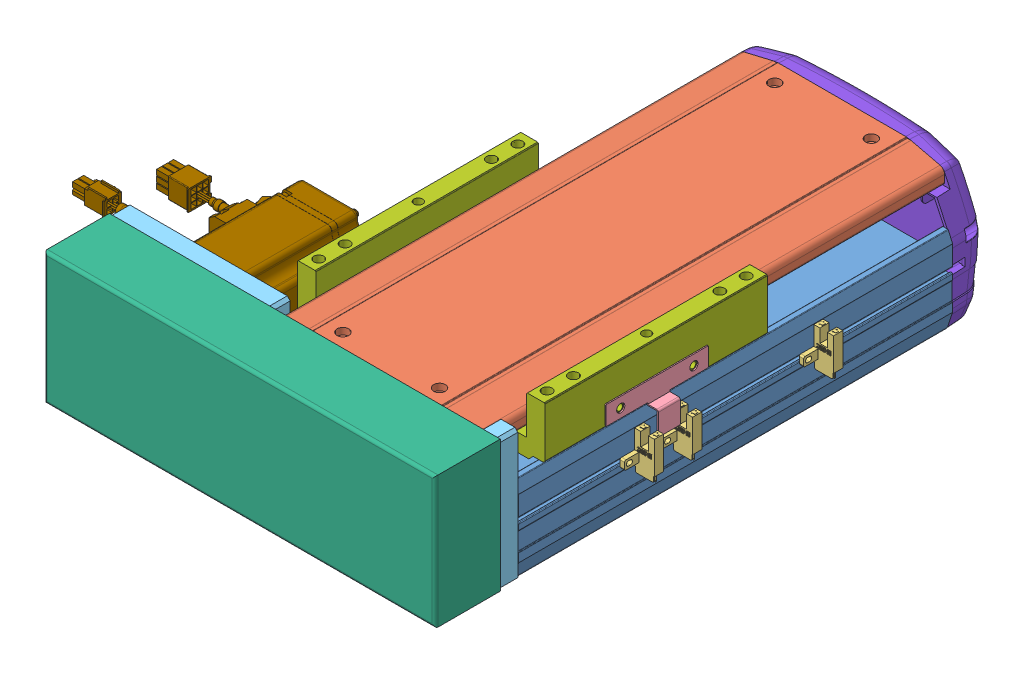
SolidWorks assembly S17-BR-400W, configuration 默认. Lengths in mm.
Overall size (347.7 97.04 383.22).
11 component instances, 9 part files, 40 mates.
Components (placement in the parent):
- S17-BM底座^S17-BR-400W-1: S17-BM底座^S17-BR-400W [默认] at origin size (170 59.5 313.5) (virtual)
- S17-BM上盖^S17-BR-400W-2: S17-BM上盖^S17-BR-400W [默认] at (0 90.5 7.5) size (140 15.5 318) (virtual)
- EE-SX672 传感器^S17-BR-400W-1: EE-SX672 传感器^S17-BR-400W [默认] at (91.7485 41.1 234.2) x (1 0 0) z (0 0 -1) size (13.5 27.4 26.1) (virtual)
- EE-SX672 传感器^S17-BR-400W-2: EE-SX672 传感器^S17-BR-400W [默认] at (91.7485 41.1 208.1) x (1 0 0) z (0 0 -1) size (13.5 27.4 26.1) (virtual)
- EE-SX672 传感器^S17-BR-400W-3: EE-SX672 传感器^S17-BR-400W [默认] at (91.7485 41.1 111.8) x (1 0 0) z (0 0 -1) size (13.5 27.4 26.1) (virtual)
- S17-BL感应片(外置)^S17-BR-400W-1: S17-BL感应片(外置)^S17-BR-400W [默认] at (84.5 76 254) size (8 30 70) (virtual)
- S17-BL-P75电机安装板左转折^S17-BR-400W-1: S17-BL-P75电机安装板左转折^S17-BR-400W [默认] at (84.5015 1 325.5) x (-1 0 0) z (0 0 -1) size (267 90 12) (virtual)
- S17-BL盖子^S17-BR-400W-1: S17-BL盖子^S17-BR-400W [默认] at (-182.4985 1 325.5) size (267 90 44.5) (virtual)
- S17-BC丝杆螺母连接座^S17-BR-400W-1: S17-BC丝杆螺母连接座^S17-BR-400W [Default] at (0 97 219) x (-1 0 0) z (0 0 -1) size (169 71 152) (virtual)
- 复件 S17塑胶端盖^S17-BR-400W-1: 复件 S17塑胶端盖^S17-BR-400W [Default] at (0 -0.0852 -13) x (-1 0 0) z (0 0 -1) size (170.72 91.84 30.22) (virtual)
- 复件 松下400W电机MHMF042L1U22^S17-BR-400W-1: 复件 松下400W电机MHMF042L1U22^S17-BR-400W [默认] at (-129.9985 49.75 313.5) x (0 0 1) z (0 -1 0) size (118 149.2 60) (virtual)
Mates (geometry in assembly coordinates):
- 距离10: distance = 97 mm: plane of S17-BC丝杆螺母连接座^S17-BR-400W-1 through (84 97 143) normal (0 1 0); plane of S17-BM底座^S17-BR-400W-1 through (0 0 313.5) normal (0 -1 0)
- 距离11: distance = 90.5 mm: plane of S17-BM上盖^S17-BR-400W-2 through (-43.7927 90.5 325.5) normal (0 1 0); plane of S17-BM底座^S17-BR-400W-1 through (0 0 313.5) normal (0 -1 0)
- 重合153: coincident: plane of S17-BM底座^S17-BR-400W-1 through (0 0 0) normal (1 0 0); plane of S17-BM上盖^S17-BR-400W-2 through (0 90.5 7.5) normal (1 0 0)
- 重合156: coincident: plane of S17-BM底座^S17-BR-400W-1 through (0 0 0) normal (1 0 0); plane of S17-BC丝杆螺母连接座^S17-BR-400W-1 through (0 97 219) normal (-1 0 0)
- 重合159: coincident: plane of EE-SX672 传感器^S17-BR-400W-1 through (84.9985 52.2 227.9) normal (0 1 0); plane of EE-SX672 传感器^S17-BR-400W-3 through (84.9985 52.2 105.5) normal (0 1 0)
- 重合160: coincident: plane of EE-SX672 传感器^S17-BR-400W-1 through (84.9985 52.2 227.9) normal (0 1 0); plane of EE-SX672 传感器^S17-BR-400W-2 through (84.9985 52.2 201.8) normal (0 1 0)
- 距离20: distance = 30 mm: plane of S17-BM底座^S17-BR-400W-1 through (0 0 313.5) normal (0 -1 0); plane of EE-SX672 传感器^S17-BR-400W-2 through (84.9985 30 201.8) normal (0 -1 0)
- 同心109: concentric: cylinder of S17-BL感应片(外置)^S17-BR-400W-1 through (84.5 69 191.8) axis (-1 0 0) radius 2.8; cylinder of S17-BC丝杆螺母连接座^S17-BR-400W-1 through (84.5 69 191.8) axis (1 0 0) radius 2.1
- 同心111: concentric: cylinder of S17-BL感应片(外置)^S17-BR-400W-1 through (84.5 69 241.8) axis (-1 0 0) radius 2.8; cylinder of S17-BC丝杆螺母连接座^S17-BR-400W-1 through (84.5 69 241.8) axis (1 0 0) radius 2.1
- 重合163: coincident: plane of S17-BC丝杆螺母连接座^S17-BR-400W-1 through (84.5 62.7074 143) normal (1 0 0); plane of S17-BL感应片(外置)^S17-BR-400W-1 through (84.5 76 254) normal (-1 0 0)
- 重合169: coincident: plane of EE-SX672 传感器^S17-BR-400W-1 through (87.9985 33.2 218) normal (0 0 -1); plane of EE-SX672 传感器^S17-BR-400W-2 through (87.9985 33.2 218) normal (0 0 1)
- 重合178: coincident: plane of S17-BL-P75电机安装板左转折^S17-BR-400W-1 through (-182.4985 1 313.5) normal (0 -1 0); plane of S17-BL盖子^S17-BR-400W-1 through (84.5015 1 325.5) normal (0 -1 0)
- 重合180: coincident: plane of S17-BM底座^S17-BR-400W-1 through (0 0 313.5) normal (0 0 1); plane of S17-BL-P75电机安装板左转折^S17-BR-400W-1 through (84.5015 91 313.5) normal (0 0 -1)
- 重合181: coincident: plane of S17-BM底座^S17-BR-400W-1 through (84.4985 0 313.5) normal (1 0 0); plane of S17-BL-P75电机安装板左转折^S17-BR-400W-1 through (84.5015 1 313.5) normal (1 0 0)
- 距离27: distance = 1 mm: plane of S17-BL-P75电机安装板左转折^S17-BR-400W-1 through (-182.4985 1 313.5) normal (0 -1 0); plane of S17-BM底座^S17-BR-400W-1 through (0 0 313.5) normal (0 -1 0)
- 重合185: coincident: plane of S17-BL-P75电机安装板左转折^S17-BR-400W-1 through (84.5015 91 325.5) normal (0 0 1); plane of S17-BL盖子^S17-BR-400W-1 through (-48.9985 46 325.5) normal (0 0 -1)
- 重合186: coincident: plane of S17-BL-P75电机安装板左转折^S17-BR-400W-1 through (-182.4985 91 313.5) normal (-1 0 0); plane of S17-BL盖子^S17-BR-400W-1 through (-182.4985 24.2 325.5) normal (-1 0 0)
- 距离30: distance = 81.5 mm: plane of EE-SX672 传感器^S17-BR-400W-1 through (98.4985 30 234.2) normal (0 0 1); plane of S17-BM底座^S17-BR-400W-1 through (0 0 313.5) normal (0 0 1)
- 重合189: coincident: plane of S17-BM上盖^S17-BR-400W-2 through (68.2998 76.7 325.5) normal (0 0 1); plane of S17-BL盖子^S17-BR-400W-1 through (-48.9985 46 325.5) normal (0 0 -1)
- 重合190: coincident: plane of S17-BM底座^S17-BR-400W-1 through (0 0 0) normal (0 0 1); plane of assembly through (0 0 0) normal (0 0 1)
- 重合191: coincident: plane of S17-BM底座^S17-BR-400W-1 through (0 0 0) normal (0 1 0); plane of assembly through (0 0 0) normal (0 1 0)
- 重合192: coincident: plane of S17-BM底座^S17-BR-400W-1 through (0 0 0) normal (1 0 0); plane of assembly through (0 0 0) normal (1 0 0)
- 距离31: distance = 105.5 mm: plane of EE-SX672 传感器^S17-BR-400W-3 through (98.4985 30 105.5) normal (0 0 -1); plane of S17-BM底座^S17-BR-400W-1 through (0 0 0) normal (0 0 -1)
- 重合193: coincident: plane of S17-BM底座^S17-BR-400W-1 through (96.5232 59.4999 17) normal (0 0 -1); plane of 复件 S17塑胶端盖^S17-BR-400W-1 through (0 -0.0852 17) normal (0 0 1)
- 重合194: coincident: line of S17-BM上盖^S17-BR-400W-2 through (43.7927 90.5 7.5) axis (-1 0 0); line of 复件 S17塑胶端盖^S17-BR-400W-1 through (43.4408 90.5 7.5) axis (-1 0 0)
- 重合195: coincident: line of S17-BM底座^S17-BR-400W-1 through (79.4985 35.3956 17) axis (0 1 0); moEndPointRef_w of 复件 S17塑胶端盖^S17-BR-400W-1
- 距离34: distance = 22.5 mm: plane of 复件 松下400W电机MHMF042L1U22^S17-BR-400W-1 through (-159.9985 74.75 242) normal (-1 0 0); plane of S17-BL-P75电机安装板左转折^S17-BR-400W-1 through (-182.4985 91 313.5) normal (-1 0 0)
- 重合196: coincident: plane of S17-BL-P75电机安装板左转折^S17-BR-400W-1 through (84.5015 1 311) normal (0 0 -1); plane of 复件 松下400W电机MHMF042L1U22^S17-BR-400W-1 through (-154.9985 24.75 311) normal (0 0 1)
- 宽度2: width: plane of S17-BL感应片(外置)^S17-BR-400W-1 through (85.3 58.7711 223.3) normal (0 0 1); plane of S17-BL感应片(外置)^S17-BR-400W-1 through (85.3 41.7711 208.3) normal (0 0 -1); plane of EE-SX672 传感器^S17-BR-400W-1 through (98.4985 30 225.7) normal (0 0 -1); plane of EE-SX672 传感器^S17-BR-400W-2 through (98.4985 30 205.9) normal (0 0 1)
- 距离35: distance = 18.75 mm: plane of 复件 松下400W电机MHMF042L1U22^S17-BR-400W-1 through (-154.9985 19.75 242) normal (0 -1 0); plane of S17-BL-P75电机安装板左转折^S17-BR-400W-1 through (-182.4985 1 313.5) normal (0 -1 0)
- 重合198: coincident: plane of EE-SX672 传感器^S17-BR-400W-1 through (98.4985 52.2 227.9) normal (1 0 0); plane of EE-SX672 传感器^S17-BR-400W-2 through (98.4985 52.2 201.8) normal (1 0 0)
- 重合199: coincident: plane of S17-BM底座^S17-BR-400W-1 through (84.9985 0 313.5) normal (1 0 0); plane of EE-SX672 传感器^S17-BR-400W-1 through (84.9985 52.2 227.9) normal (-1 0 0)
- 重合200: coincident: plane of EE-SX672 传感器^S17-BR-400W-2 through (98.4985 52.2 201.8) normal (1 0 0); plane of EE-SX672 传感器^S17-BR-400W-3 through (98.4985 52.2 105.5) normal (1 0 0)
- 距离36: distance = 45 mm: cylinder of 复件 松下400W电机MHMF042L1U22^S17-BR-400W-1 through (-129.9985 49.75 343.5) axis (0 0 -1) radius 7; plane of S17-BM底座^S17-BR-400W-1 through (-84.9985 0 313.5) normal (-1 0 0)
- 距离37: distance = 49.75 mm: cylinder of 复件 松下400W电机MHMF042L1U22^S17-BR-400W-1 through (-129.9985 49.75 343.5) axis (0 0 -1) radius 7; plane of S17-BM底座^S17-BR-400W-1 through (0 0 313.5) normal (0 -1 0)
- 重合201: coincident: plane of S17-BL-P75电机安装板左转折^S17-BR-400W-1 through (84.5015 91 313.5) normal (0 0 -1); plane of 复件 松下400W电机MHMF042L1U22^S17-BR-400W-1 through (-154.9985 24.75 313.5) normal (0 0 1)
- 距离41: distance = 151 mm: plane of S17-BL盖子^S17-BR-400W-1 through (-48.9985 46 370) normal (0 0 1); cylinder of S17-BC丝杆螺母连接座^S17-BR-400W-1 through (78 97 219) axis (0 1 0) radius 3
- 同心112: concentric: cylinder of S17-BL感应片(外置)^S17-BR-400W-1 through (84.5 69 244) axis (-1 0 0) radius 2.8; cylinder of S17-BC丝杆螺母连接座^S17-BR-400W-1 through (84.5 69 244) axis (1 0 0) radius 2.1
- 同心113: concentric: cylinder of S17-BC丝杆螺母连接座^S17-BR-400W-1 through (84.5 69 194) axis (1 0 0) radius 2.1; cylinder of S17-BL感应片(外置)^S17-BR-400W-1 through (84.5 69 194) axis (-1 0 0) radius 2.8
- 宽度3: width: plane of EE-SX672 传感器^S17-BR-400W-1 through (98.4985 30 227.9) normal (0 0 -1); plane of EE-SX672 传感器^S17-BR-400W-2 through (98.4985 30 208.1) normal (0 0 1); plane of S17-BL感应片(外置)^S17-BR-400W-1 through (85.3 46 210.5) normal (0 0 -1); plane of S17-BL感应片(外置)^S17-BR-400W-1 through (85.3 63 225.5) normal (0 0 1)
